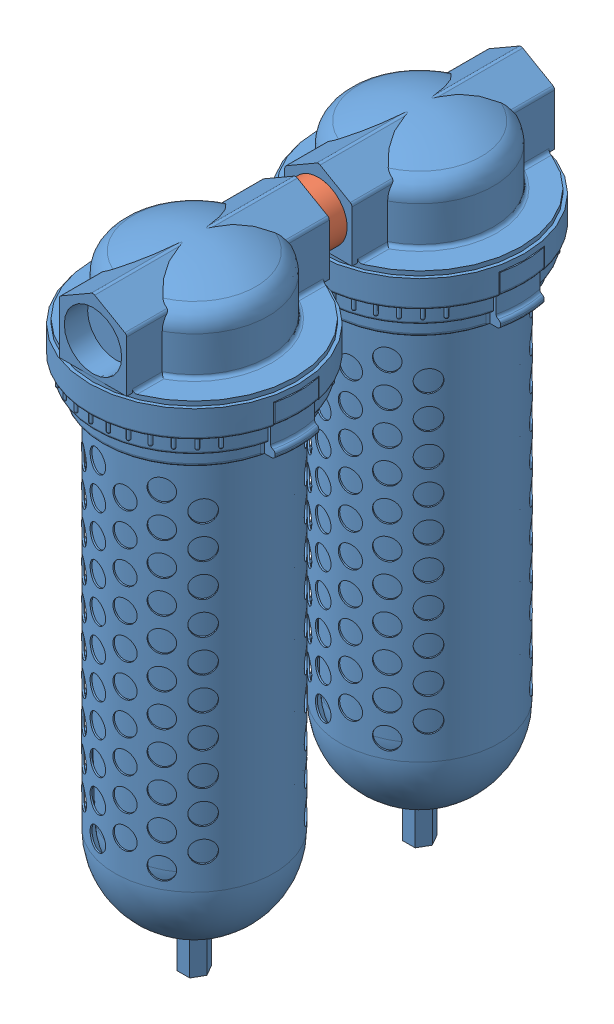
SolidWorks assembly ReadingTech_3P-090-P08-DC, configuration Default. Lengths in mm.
Overall size (121.86 369.43 252.73).
3 component instances, 2 part files, 3 mates.
Components (placement in the parent):
- ReadingTech_3P090P08F-1: ReadingTech_3P090P08F [Default] at (-64.7317 -220.1342 28.5756) size (121.86 369.43 121.67)
- ReadingTech_3P090P08F-2: ReadingTech_3P090P08F [Default] at (-64.7317 -220.1342 -102.4884) size (121.86 369.43 121.67)
- ReadingTech- 90,150cfm_connector_1in-1: ReadingTech- 90,150cfm_connector_1in [Default] at (-64.7317 168.8668 -30.3524) x (1 0 0) z (0 1 0) size (33.4 13.21 33.4)
Mates (geometry in assembly coordinates):
- Coincident1: coincident anti-aligned: circle of ReadingTech_3P090P08F-2; circle of ReadingTech- 90,150cfm_connector_1in-1
- Coincident2: coincident aligned: circle of ReadingTech_3P090P08F-1; circle of ReadingTech- 90,150cfm_connector_1in-1
- Coincident3: coincident aligned: plane of ReadingTech_3P090P08F-1 through (-45.1737 181.5668 87.5036) normal (1 0 0); plane of ReadingTech_3P090P08F-2 through (-45.1737 181.5668 -43.5604) normal (1 0 0)
